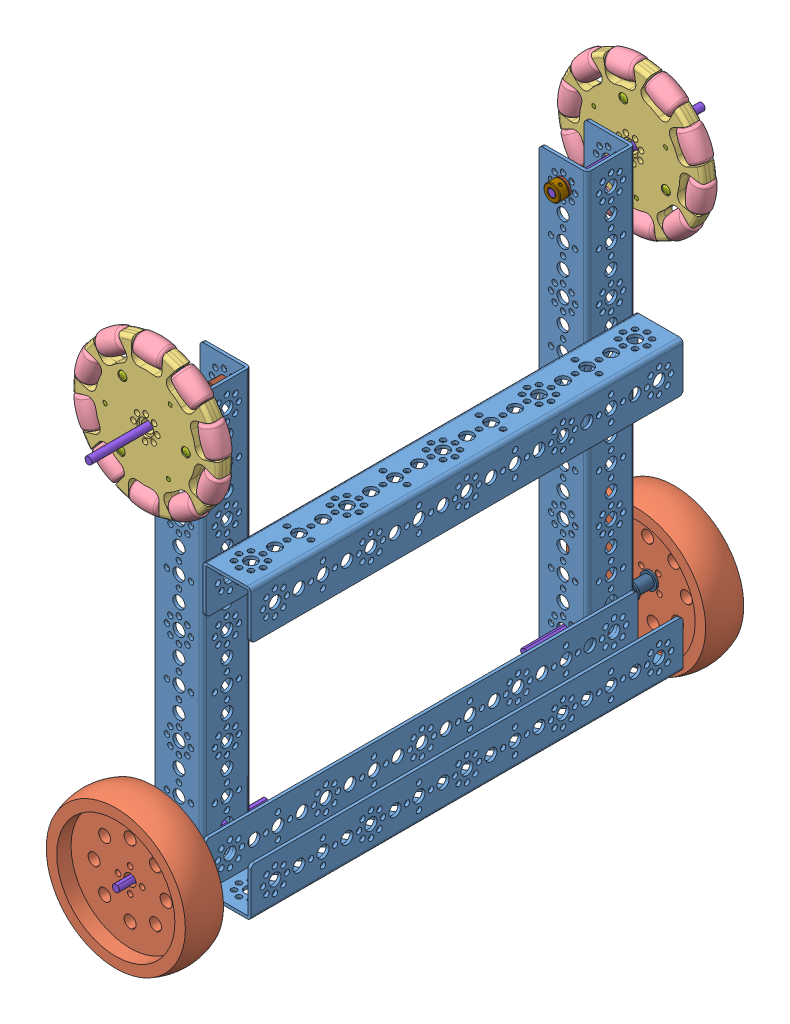
SolidWorks assembly Assem1, configuration Default. Lengths in mm.
Overall size (138.06 393.16 408.8).
138 component instances, 11 part files, 46 mates.
Components (placement in the parent):
- Copy of tetrix_739068^Assem1-1: Copy of tetrix_739068^Assem1 [Default] at origin size (32 32 288) (virtual)
- Copy of tetrix_739068^Assem1-2: Copy of tetrix_739068^Assem1 [Default] at (0 192 0) x (-1 0 0) z (0 0 1) size (32 32 288) (virtual)
- Copy of tetrix_739068^Assem1-3: Copy of tetrix_739068^Assem1 [Default] at (-16 272 -256) x (0 0 -1) z (0 1 0) size (32 32 288) (virtual)
- Copy of tetrix_739068^Assem1-5: Copy of tetrix_739068^Assem1 [Default] at (-16 272 0) x (0 0 -1) z (0 1 0) size (32 32 288) (virtual)
- Copy of tetrix_739055^Assem1-1: Copy of tetrix_739055^Assem1 [Default] at (-32 16 -301.375) x (0.758888 -0.651221 0) z (0 0 1) size (97.6 97.6 25.4) (virtual)
- Copy of tetrix_739055^Assem1-2: Copy of tetrix_739055^Assem1 [Default] at (-32 16 45.375) size (97.6 97.6 25.4) (virtual)
- Copy of tetrix_731132^Assem1-1: Copy of tetrix_731132^Assem1 [Default] at (-32 272 -289.4) x (0.892006 -0.452024 0) z (-0.452024 -0.892006 0) size (103.76 14.46 100.67) (virtual)
  - Copy of tetrix_731132_hub^Copy of tetrix_731132_Assem1-1: Copy of tetrix_731132_hub^Copy of tetrix_731132_Assem1 [Default] at origin size (98 5.15 96.15) (virtual)
  - Copy of tetrix_731132_roller_asm^Copy of tetrix_731132_Assem1-1: Copy of tetrix_731132_roller_asm^Copy of tetrix_731132_Assem1 [Default] at (-0.077 -0.125 43.105) x (1 0 0) z (0 0 -1) size (25.8 14.46 14.46) (virtual)
    - Copy of tetrix_731132_roller^Copy of tetrix_731132_roller_asm_Copy of tetrix_731132_Assem1-1: Copy of tetrix_731132_roller^Copy of tetrix_731132_roller_asm_Copy of tetrix_731132_Assem1 [Default] at origin size (19 14.46 14.46) (virtual)
    - Copy of tetrix_731132_roller_axle^Copy of tetrix_731132_roller_asm_Copy of tetrix_731132_Assem1-1: Copy of tetrix_731132_roller_axle^Copy of tetrix_731132_roller_asm_Copy of tetrix_731132_Assem1 [Default] x (0 0 1) z (-1 0 0) size (3 3 24) (virtual)
    - tetrix_731132_bearing-1: tetrix_731132_bearing [Default] at (-12.9 0 0) x (0 0 -1) z (1 0 0) size (3.25 3.25 3.4)
    - tetrix_731132_bearing-2: tetrix_731132_bearing [Default] at (12.9 0 0) x (0 0 1) z (-1 0 0) size (3.25 3.25 3.4)
  - Copy of tetrix_731132_roller_asm^Copy of tetrix_731132_Assem1-2: Copy of tetrix_731132_roller_asm^Copy of tetrix_731132_Assem1 [Default] at (25.2742 -0.125 34.9179) x (0.809017 0 -0.587785) z (-0.587785 0 -0.809017) size (25.8 14.46 14.46) (virtual)
    - Copy of tetrix_731132_roller^Copy of tetrix_731132_roller_asm_Copy of tetrix_731132_Assem1-1: Copy of tetrix_731132_roller^Copy of tetrix_731132_roller_asm_Copy of tetrix_731132_Assem1 [Default] at origin size (19 14.46 14.46) (virtual)
    - Copy of tetrix_731132_roller_axle^Copy of tetrix_731132_roller_asm_Copy of tetrix_731132_Assem1-1: Copy of tetrix_731132_roller_axle^Copy of tetrix_731132_roller_asm_Copy of tetrix_731132_Assem1 [Default] x (0 0 1) z (-1 0 0) size (3 3 24) (virtual)
    - tetrix_731132_bearing-1: tetrix_731132_bearing [Default] at (-12.9 0 0) x (0 0 -1) z (1 0 0) size (3.25 3.25 3.4)
    - tetrix_731132_bearing-2: tetrix_731132_bearing [Default] at (12.9 0 0) x (0 0 1) z (-1 0 0) size (3.25 3.25 3.4)
  - Copy of tetrix_731132_roller_asm^Copy of tetrix_731132_Assem1-3: Copy of tetrix_731132_roller_asm^Copy of tetrix_731132_Assem1 [Default] at (40.9715 -0.125 13.3934) x (0.309017 0 -0.951057) z (-0.951057 0 -0.309017) size (25.8 14.46 14.46) (virtual)
    - Copy of tetrix_731132_roller^Copy of tetrix_731132_roller_asm_Copy of tetrix_731132_Assem1-1: Copy of tetrix_731132_roller^Copy of tetrix_731132_roller_asm_Copy of tetrix_731132_Assem1 [Default] at origin size (19 14.46 14.46) (virtual)
    - Copy of tetrix_731132_roller_axle^Copy of tetrix_731132_roller_asm_Copy of tetrix_731132_Assem1-1: Copy of tetrix_731132_roller_axle^Copy of tetrix_731132_roller_asm_Copy of tetrix_731132_Assem1 [Default] x (0 0 1) z (-1 0 0) size (3 3 24) (virtual)
    - tetrix_731132_bearing-1: tetrix_731132_bearing [Default] at (-12.9 0 0) x (0 0 -1) z (1 0 0) size (3.25 3.25 3.4)
    - tetrix_731132_bearing-2: tetrix_731132_bearing [Default] at (12.9 0 0) x (0 0 1) z (-1 0 0) size (3.25 3.25 3.4)
  - Copy of tetrix_731132_roller_asm^Copy of tetrix_731132_Assem1-4: Copy of tetrix_731132_roller_asm^Copy of tetrix_731132_Assem1 [Default] at (41.0191 -0.125 -13.2469) x (-0.309017 0 -0.951057) z (-0.951057 0 0.309017) size (25.8 14.46 14.46) (virtual)
    - Copy of tetrix_731132_roller^Copy of tetrix_731132_roller_asm_Copy of tetrix_731132_Assem1-1: Copy of tetrix_731132_roller^Copy of tetrix_731132_roller_asm_Copy of tetrix_731132_Assem1 [Default] at origin size (19 14.46 14.46) (virtual)
    - Copy of tetrix_731132_roller_axle^Copy of tetrix_731132_roller_asm_Copy of tetrix_731132_Assem1-1: Copy of tetrix_731132_roller_axle^Copy of tetrix_731132_roller_asm_Copy of tetrix_731132_Assem1 [Default] x (0 0 1) z (-1 0 0) size (3 3 24) (virtual)
    - tetrix_731132_bearing-1: tetrix_731132_bearing [Default] at (-12.9 0 0) x (0 0 -1) z (1 0 0) size (3.25 3.25 3.4)
    - tetrix_731132_bearing-2: tetrix_731132_bearing [Default] at (12.9 0 0) x (0 0 1) z (-1 0 0) size (3.25 3.25 3.4)
  - Copy of tetrix_731132_roller_asm^Copy of tetrix_731132_Assem1-5: Copy of tetrix_731132_roller_asm^Copy of tetrix_731132_Assem1 [Default] at (25.3988 -0.125 -34.8274) x (-0.809017 0 -0.587785) z (-0.587785 0 0.809017) size (25.8 14.46 14.46) (virtual)
    - Copy of tetrix_731132_roller^Copy of tetrix_731132_roller_asm_Copy of tetrix_731132_Assem1-1: Copy of tetrix_731132_roller^Copy of tetrix_731132_roller_asm_Copy of tetrix_731132_Assem1 [Default] at origin size (19 14.46 14.46) (virtual)
    - Copy of tetrix_731132_roller_axle^Copy of tetrix_731132_roller_asm_Copy of tetrix_731132_Assem1-1: Copy of tetrix_731132_roller_axle^Copy of tetrix_731132_roller_asm_Copy of tetrix_731132_Assem1 [Default] x (0 0 1) z (-1 0 0) size (3 3 24) (virtual)
    - tetrix_731132_bearing-1: tetrix_731132_bearing [Default] at (-12.9 0 0) x (0 0 -1) z (1 0 0) size (3.25 3.25 3.4)
    - tetrix_731132_bearing-2: tetrix_731132_bearing [Default] at (12.9 0 0) x (0 0 1) z (-1 0 0) size (3.25 3.25 3.4)
  - Copy of tetrix_731132_roller_asm^Copy of tetrix_731132_Assem1-6: Copy of tetrix_731132_roller_asm^Copy of tetrix_731132_Assem1 [Default] at (0.077 -0.125 -43.105) x (-1 0 0) z (0 0 1) size (25.8 14.46 14.46) (virtual)
    - Copy of tetrix_731132_roller^Copy of tetrix_731132_roller_asm_Copy of tetrix_731132_Assem1-1: Copy of tetrix_731132_roller^Copy of tetrix_731132_roller_asm_Copy of tetrix_731132_Assem1 [Default] at origin size (19 14.46 14.46) (virtual)
    - Copy of tetrix_731132_roller_axle^Copy of tetrix_731132_roller_asm_Copy of tetrix_731132_Assem1-1: Copy of tetrix_731132_roller_axle^Copy of tetrix_731132_roller_asm_Copy of tetrix_731132_Assem1 [Default] x (0 0 1) z (-1 0 0) size (3 3 24) (virtual)
    - tetrix_731132_bearing-1: tetrix_731132_bearing [Default] at (-12.9 0 0) x (0 0 -1) z (1 0 0) size (3.25 3.25 3.4)
    - tetrix_731132_bearing-2: tetrix_731132_bearing [Default] at (12.9 0 0) x (0 0 1) z (-1 0 0) size (3.25 3.25 3.4)
  - Copy of tetrix_731132_roller_asm^Copy of tetrix_731132_Assem1-7: Copy of tetrix_731132_roller_asm^Copy of tetrix_731132_Assem1 [Default] at (-25.2742 -0.125 -34.9179) x (-0.809017 0 0.587785) z (0.587785 0 0.809017) size (25.8 14.46 14.46) (virtual)
    - Copy of tetrix_731132_roller^Copy of tetrix_731132_roller_asm_Copy of tetrix_731132_Assem1-1: Copy of tetrix_731132_roller^Copy of tetrix_731132_roller_asm_Copy of tetrix_731132_Assem1 [Default] at origin size (19 14.46 14.46) (virtual)
    - Copy of tetrix_731132_roller_axle^Copy of tetrix_731132_roller_asm_Copy of tetrix_731132_Assem1-1: Copy of tetrix_731132_roller_axle^Copy of tetrix_731132_roller_asm_Copy of tetrix_731132_Assem1 [Default] x (0 0 1) z (-1 0 0) size (3 3 24) (virtual)
    - tetrix_731132_bearing-1: tetrix_731132_bearing [Default] at (-12.9 0 0) x (0 0 -1) z (1 0 0) size (3.25 3.25 3.4)
    - tetrix_731132_bearing-2: tetrix_731132_bearing [Default] at (12.9 0 0) x (0 0 1) z (-1 0 0) size (3.25 3.25 3.4)
  - Copy of tetrix_731132_roller_asm^Copy of tetrix_731132_Assem1-8: Copy of tetrix_731132_roller_asm^Copy of tetrix_731132_Assem1 [Default] at (-40.9715 -0.125 -13.3934) x (-0.309017 0 0.951057) z (0.951057 0 0.309017) size (25.8 14.46 14.46) (virtual)
    - Copy of tetrix_731132_roller^Copy of tetrix_731132_roller_asm_Copy of tetrix_731132_Assem1-1: Copy of tetrix_731132_roller^Copy of tetrix_731132_roller_asm_Copy of tetrix_731132_Assem1 [Default] at origin size (19 14.46 14.46) (virtual)
    - Copy of tetrix_731132_roller_axle^Copy of tetrix_731132_roller_asm_Copy of tetrix_731132_Assem1-1: Copy of tetrix_731132_roller_axle^Copy of tetrix_731132_roller_asm_Copy of tetrix_731132_Assem1 [Default] x (0 0 1) z (-1 0 0) size (3 3 24) (virtual)
    - tetrix_731132_bearing-1: tetrix_731132_bearing [Default] at (-12.9 0 0) x (0 0 -1) z (1 0 0) size (3.25 3.25 3.4)
    - tetrix_731132_bearing-2: tetrix_731132_bearing [Default] at (12.9 0 0) x (0 0 1) z (-1 0 0) size (3.25 3.25 3.4)
  - Copy of tetrix_731132_roller_asm^Copy of tetrix_731132_Assem1-9: Copy of tetrix_731132_roller_asm^Copy of tetrix_731132_Assem1 [Default] at (-41.0191 -0.125 13.2469) x (0.309017 0 0.951057) z (0.951057 0 -0.309017) size (25.8 14.46 14.46) (virtual)
    - Copy of tetrix_731132_roller^Copy of tetrix_731132_roller_asm_Copy of tetrix_731132_Assem1-1: Copy of tetrix_731132_roller^Copy of tetrix_731132_roller_asm_Copy of tetrix_731132_Assem1 [Default] at origin size (19 14.46 14.46) (virtual)
    - Copy of tetrix_731132_roller_axle^Copy of tetrix_731132_roller_asm_Copy of tetrix_731132_Assem1-1: Copy of tetrix_731132_roller_axle^Copy of tetrix_731132_roller_asm_Copy of tetrix_731132_Assem1 [Default] x (0 0 1) z (-1 0 0) size (3 3 24) (virtual)
    - tetrix_731132_bearing-1: tetrix_731132_bearing [Default] at (-12.9 0 0) x (0 0 -1) z (1 0 0) size (3.25 3.25 3.4)
    - tetrix_731132_bearing-2: tetrix_731132_bearing [Default] at (12.9 0 0) x (0 0 1) z (-1 0 0) size (3.25 3.25 3.4)
  - Copy of tetrix_731132_roller_asm^Copy of tetrix_731132_Assem1-10: Copy of tetrix_731132_roller_asm^Copy of tetrix_731132_Assem1 [Default] at (-25.3988 -0.125 34.8274) x (0.809017 0 0.587785) z (0.587785 0 -0.809017) size (25.8 14.46 14.46) (virtual)
    - Copy of tetrix_731132_roller^Copy of tetrix_731132_roller_asm_Copy of tetrix_731132_Assem1-1: Copy of tetrix_731132_roller^Copy of tetrix_731132_roller_asm_Copy of tetrix_731132_Assem1 [Default] at origin size (19 14.46 14.46) (virtual)
    - Copy of tetrix_731132_roller_axle^Copy of tetrix_731132_roller_asm_Copy of tetrix_731132_Assem1-1: Copy of tetrix_731132_roller_axle^Copy of tetrix_731132_roller_asm_Copy of tetrix_731132_Assem1 [Default] x (0 0 1) z (-1 0 0) size (3 3 24) (virtual)
    - tetrix_731132_bearing-1: tetrix_731132_bearing [Default] at (-12.9 0 0) x (0 0 -1) z (1 0 0) size (3.25 3.25 3.4)
    - tetrix_731132_bearing-2: tetrix_731132_bearing [Default] at (12.9 0 0) x (0 0 1) z (-1 0 0) size (3.25 3.25 3.4)
  - Copy of tetrix_731132_hub^Copy of tetrix_731132_Assem1-2: Copy of tetrix_731132_hub^Copy of tetrix_731132_Assem1 [Default] x (-1 0 0) z (0 0 1) size (98 5.15 96.15) (virtual)
  - tetrix_731132_screw-1: tetrix_731132_screw [Default] at (-27 -3 0) x (-0.837169 0 -0.546944) z (-0.546944 0 0.837169) size (5.6 10.48 5.64)
  - tetrix_731132_screw-2: tetrix_731132_screw [Default] at (27 3 0) size (5.6 10.48 5.64)
  - tetrix_731132_screw-7: tetrix_731132_screw [Default] at (-15.8702 3 21.8435) size (5.6 10.48 5.64)
  - tetrix_731132_screw-8: tetrix_731132_screw [Default] at (-15.8702 3 -21.8435) size (5.6 10.48 5.64)
  - tetrix_731132_screw-9: tetrix_731132_screw [Default] at (15.8702 -3 21.8435) x (-0.837169 0 -0.546944) z (-0.546944 0 0.837169) size (5.6 10.48 5.64)
  - tetrix_731132_screw-10: tetrix_731132_screw [Default] at (15.8702 -3 -21.8435) x (-0.837169 0 -0.546944) z (-0.546944 0 0.837169) size (5.6 10.48 5.64)
- Copy of tetrix_731132^Assem1-2: Copy of tetrix_731132^Assem1 [Default] at (-32 272 33.4) x (0.999671 -0.025666 0) z (-0.025666 -0.999671 0) size (103.76 14.46 100.67) (virtual)
  - Copy of tetrix_731132_hub^Copy of tetrix_731132_Assem1-1: Copy of tetrix_731132_hub^Copy of tetrix_731132_Assem1 [Default] at origin size (98 5.15 96.15) (virtual)
  - Copy of tetrix_731132_roller_asm^Copy of tetrix_731132_Assem1-1: Copy of tetrix_731132_roller_asm^Copy of tetrix_731132_Assem1 [Default] at (-0.077 -0.125 43.105) x (1 0 0) z (0 0 -1) size (25.8 14.46 14.46) (virtual)
    - Copy of tetrix_731132_roller^Copy of tetrix_731132_roller_asm_Copy of tetrix_731132_Assem1-1: Copy of tetrix_731132_roller^Copy of tetrix_731132_roller_asm_Copy of tetrix_731132_Assem1 [Default] at origin size (19 14.46 14.46) (virtual)
    - Copy of tetrix_731132_roller_axle^Copy of tetrix_731132_roller_asm_Copy of tetrix_731132_Assem1-1: Copy of tetrix_731132_roller_axle^Copy of tetrix_731132_roller_asm_Copy of tetrix_731132_Assem1 [Default] x (0 0 1) z (-1 0 0) size (3 3 24) (virtual)
    - tetrix_731132_bearing-1: tetrix_731132_bearing [Default] at (-12.9 0 0) x (0 0 -1) z (1 0 0) size (3.25 3.25 3.4)
    - tetrix_731132_bearing-2: tetrix_731132_bearing [Default] at (12.9 0 0) x (0 0 1) z (-1 0 0) size (3.25 3.25 3.4)
  - Copy of tetrix_731132_roller_asm^Copy of tetrix_731132_Assem1-2: Copy of tetrix_731132_roller_asm^Copy of tetrix_731132_Assem1 [Default] at (25.2742 -0.125 34.9179) x (0.809017 0 -0.587785) z (-0.587785 0 -0.809017) size (25.8 14.46 14.46) (virtual)
    - Copy of tetrix_731132_roller^Copy of tetrix_731132_roller_asm_Copy of tetrix_731132_Assem1-1: Copy of tetrix_731132_roller^Copy of tetrix_731132_roller_asm_Copy of tetrix_731132_Assem1 [Default] at origin size (19 14.46 14.46) (virtual)
    - Copy of tetrix_731132_roller_axle^Copy of tetrix_731132_roller_asm_Copy of tetrix_731132_Assem1-1: Copy of tetrix_731132_roller_axle^Copy of tetrix_731132_roller_asm_Copy of tetrix_731132_Assem1 [Default] x (0 0 1) z (-1 0 0) size (3 3 24) (virtual)
    - tetrix_731132_bearing-1: tetrix_731132_bearing [Default] at (-12.9 0 0) x (0 0 -1) z (1 0 0) size (3.25 3.25 3.4)
    - tetrix_731132_bearing-2: tetrix_731132_bearing [Default] at (12.9 0 0) x (0 0 1) z (-1 0 0) size (3.25 3.25 3.4)
  - Copy of tetrix_731132_roller_asm^Copy of tetrix_731132_Assem1-3: Copy of tetrix_731132_roller_asm^Copy of tetrix_731132_Assem1 [Default] at (40.9715 -0.125 13.3934) x (0.309017 0 -0.951057) z (-0.951057 0 -0.309017) size (25.8 14.46 14.46) (virtual)
    - Copy of tetrix_731132_roller^Copy of tetrix_731132_roller_asm_Copy of tetrix_731132_Assem1-1: Copy of tetrix_731132_roller^Copy of tetrix_731132_roller_asm_Copy of tetrix_731132_Assem1 [Default] at origin size (19 14.46 14.46) (virtual)
    - Copy of tetrix_731132_roller_axle^Copy of tetrix_731132_roller_asm_Copy of tetrix_731132_Assem1-1: Copy of tetrix_731132_roller_axle^Copy of tetrix_731132_roller_asm_Copy of tetrix_731132_Assem1 [Default] x (0 0 1) z (-1 0 0) size (3 3 24) (virtual)
    - tetrix_731132_bearing-1: tetrix_731132_bearing [Default] at (-12.9 0 0) x (0 0 -1) z (1 0 0) size (3.25 3.25 3.4)
    - tetrix_731132_bearing-2: tetrix_731132_bearing [Default] at (12.9 0 0) x (0 0 1) z (-1 0 0) size (3.25 3.25 3.4)
  - Copy of tetrix_731132_roller_asm^Copy of tetrix_731132_Assem1-4: Copy of tetrix_731132_roller_asm^Copy of tetrix_731132_Assem1 [Default] at (41.0191 -0.125 -13.2469) x (-0.309017 0 -0.951057) z (-0.951057 0 0.309017) size (25.8 14.46 14.46) (virtual)
    - Copy of tetrix_731132_roller^Copy of tetrix_731132_roller_asm_Copy of tetrix_731132_Assem1-1: Copy of tetrix_731132_roller^Copy of tetrix_731132_roller_asm_Copy of tetrix_731132_Assem1 [Default] at origin size (19 14.46 14.46) (virtual)
    - Copy of tetrix_731132_roller_axle^Copy of tetrix_731132_roller_asm_Copy of tetrix_731132_Assem1-1: Copy of tetrix_731132_roller_axle^Copy of tetrix_731132_roller_asm_Copy of tetrix_731132_Assem1 [Default] x (0 0 1) z (-1 0 0) size (3 3 24) (virtual)
    - tetrix_731132_bearing-1: tetrix_731132_bearing [Default] at (-12.9 0 0) x (0 0 -1) z (1 0 0) size (3.25 3.25 3.4)
    - tetrix_731132_bearing-2: tetrix_731132_bearing [Default] at (12.9 0 0) x (0 0 1) z (-1 0 0) size (3.25 3.25 3.4)
  - Copy of tetrix_731132_roller_asm^Copy of tetrix_731132_Assem1-5: Copy of tetrix_731132_roller_asm^Copy of tetrix_731132_Assem1 [Default] at (25.3988 -0.125 -34.8274) x (-0.809017 0 -0.587785) z (-0.587785 0 0.809017) size (25.8 14.46 14.46) (virtual)
    - Copy of tetrix_731132_roller^Copy of tetrix_731132_roller_asm_Copy of tetrix_731132_Assem1-1: Copy of tetrix_731132_roller^Copy of tetrix_731132_roller_asm_Copy of tetrix_731132_Assem1 [Default] at origin size (19 14.46 14.46) (virtual)
    - Copy of tetrix_731132_roller_axle^Copy of tetrix_731132_roller_asm_Copy of tetrix_731132_Assem1-1: Copy of tetrix_731132_roller_axle^Copy of tetrix_731132_roller_asm_Copy of tetrix_731132_Assem1 [Default] x (0 0 1) z (-1 0 0) size (3 3 24) (virtual)
    - tetrix_731132_bearing-1: tetrix_731132_bearing [Default] at (-12.9 0 0) x (0 0 -1) z (1 0 0) size (3.25 3.25 3.4)
    - tetrix_731132_bearing-2: tetrix_731132_bearing [Default] at (12.9 0 0) x (0 0 1) z (-1 0 0) size (3.25 3.25 3.4)
  - Copy of tetrix_731132_roller_asm^Copy of tetrix_731132_Assem1-6: Copy of tetrix_731132_roller_asm^Copy of tetrix_731132_Assem1 [Default] at (0.077 -0.125 -43.105) x (-1 0 0) z (0 0 1) size (25.8 14.46 14.46) (virtual)
    - Copy of tetrix_731132_roller^Copy of tetrix_731132_roller_asm_Copy of tetrix_731132_Assem1-1: Copy of tetrix_731132_roller^Copy of tetrix_731132_roller_asm_Copy of tetrix_731132_Assem1 [Default] at origin size (19 14.46 14.46) (virtual)
    - Copy of tetrix_731132_roller_axle^Copy of tetrix_731132_roller_asm_Copy of tetrix_731132_Assem1-1: Copy of tetrix_731132_roller_axle^Copy of tetrix_731132_roller_asm_Copy of tetrix_731132_Assem1 [Default] x (0 0 1) z (-1 0 0) size (3 3 24) (virtual)
    - tetrix_731132_bearing-1: tetrix_731132_bearing [Default] at (-12.9 0 0) x (0 0 -1) z (1 0 0) size (3.25 3.25 3.4)
    - tetrix_731132_bearing-2: tetrix_731132_bearing [Default] at (12.9 0 0) x (0 0 1) z (-1 0 0) size (3.25 3.25 3.4)
  - Copy of tetrix_731132_roller_asm^Copy of tetrix_731132_Assem1-7: Copy of tetrix_731132_roller_asm^Copy of tetrix_731132_Assem1 [Default] at (-25.2742 -0.125 -34.9179) x (-0.809017 0 0.587785) z (0.587785 0 0.809017) size (25.8 14.46 14.46) (virtual)
    - Copy of tetrix_731132_roller^Copy of tetrix_731132_roller_asm_Copy of tetrix_731132_Assem1-1: Copy of tetrix_731132_roller^Copy of tetrix_731132_roller_asm_Copy of tetrix_731132_Assem1 [Default] at origin size (19 14.46 14.46) (virtual)
    - Copy of tetrix_731132_roller_axle^Copy of tetrix_731132_roller_asm_Copy of tetrix_731132_Assem1-1: Copy of tetrix_731132_roller_axle^Copy of tetrix_731132_roller_asm_Copy of tetrix_731132_Assem1 [Default] x (0 0 1) z (-1 0 0) size (3 3 24) (virtual)
    - tetrix_731132_bearing-1: tetrix_731132_bearing [Default] at (-12.9 0 0) x (0 0 -1) z (1 0 0) size (3.25 3.25 3.4)
    - tetrix_731132_bearing-2: tetrix_731132_bearing [Default] at (12.9 0 0) x (0 0 1) z (-1 0 0) size (3.25 3.25 3.4)
  - Copy of tetrix_731132_roller_asm^Copy of tetrix_731132_Assem1-8: Copy of tetrix_731132_roller_asm^Copy of tetrix_731132_Assem1 [Default] at (-40.9715 -0.125 -13.3934) x (-0.309017 0 0.951057) z (0.951057 0 0.309017) size (25.8 14.46 14.46) (virtual)
    - Copy of tetrix_731132_roller^Copy of tetrix_731132_roller_asm_Copy of tetrix_731132_Assem1-1: Copy of tetrix_731132_roller^Copy of tetrix_731132_roller_asm_Copy of tetrix_731132_Assem1 [Default] at origin size (19 14.46 14.46) (virtual)
    - Copy of tetrix_731132_roller_axle^Copy of tetrix_731132_roller_asm_Copy of tetrix_731132_Assem1-1: Copy of tetrix_731132_roller_axle^Copy of tetrix_731132_roller_asm_Copy of tetrix_731132_Assem1 [Default] x (0 0 1) z (-1 0 0) size (3 3 24) (virtual)
    - tetrix_731132_bearing-1: tetrix_731132_bearing [Default] at (-12.9 0 0) x (0 0 -1) z (1 0 0) size (3.25 3.25 3.4)
    - tetrix_731132_bearing-2: tetrix_731132_bearing [Default] at (12.9 0 0) x (0 0 1) z (-1 0 0) size (3.25 3.25 3.4)
  - Copy of tetrix_731132_roller_asm^Copy of tetrix_731132_Assem1-9: Copy of tetrix_731132_roller_asm^Copy of tetrix_731132_Assem1 [Default] at (-41.0191 -0.125 13.2469) x (0.309017 0 0.951057) z (0.951057 0 -0.309017) size (25.8 14.46 14.46) (virtual)
    - Copy of tetrix_731132_roller^Copy of tetrix_731132_roller_asm_Copy of tetrix_731132_Assem1-1: Copy of tetrix_731132_roller^Copy of tetrix_731132_roller_asm_Copy of tetrix_731132_Assem1 [Default] at origin size (19 14.46 14.46) (virtual)
    - Copy of tetrix_731132_roller_axle^Copy of tetrix_731132_roller_asm_Copy of tetrix_731132_Assem1-1: Copy of tetrix_731132_roller_axle^Copy of tetrix_731132_roller_asm_Copy of tetrix_731132_Assem1 [Default] x (0 0 1) z (-1 0 0) size (3 3 24) (virtual)
    - tetrix_731132_bearing-1: tetrix_731132_bearing [Default] at (-12.9 0 0) x (0 0 -1) z (1 0 0) size (3.25 3.25 3.4)
    - tetrix_731132_bearing-2: tetrix_731132_bearing [Default] at (12.9 0 0) x (0 0 1) z (-1 0 0) size (3.25 3.25 3.4)
  - Copy of tetrix_731132_roller_asm^Copy of tetrix_731132_Assem1-10: Copy of tetrix_731132_roller_asm^Copy of tetrix_731132_Assem1 [Default] at (-25.3988 -0.125 34.8274) x (0.809017 0 0.587785) z (0.587785 0 -0.809017) size (25.8 14.46 14.46) (virtual)
    - Copy of tetrix_731132_roller^Copy of tetrix_731132_roller_asm_Copy of tetrix_731132_Assem1-1: Copy of tetrix_731132_roller^Copy of tetrix_731132_roller_asm_Copy of tetrix_731132_Assem1 [Default] at origin size (19 14.46 14.46) (virtual)
    - Copy of tetrix_731132_roller_axle^Copy of tetrix_731132_roller_asm_Copy of tetrix_731132_Assem1-1: Copy of tetrix_731132_roller_axle^Copy of tetrix_731132_roller_asm_Copy of tetrix_731132_Assem1 [Default] x (0 0 1) z (-1 0 0) size (3 3 24) (virtual)
    - tetrix_731132_bearing-1: tetrix_731132_bearing [Default] at (-12.9 0 0) x (0 0 -1) z (1 0 0) size (3.25 3.25 3.4)
    - tetrix_731132_bearing-2: tetrix_731132_bearing [Default] at (12.9 0 0) x (0 0 1) z (-1 0 0) size (3.25 3.25 3.4)
  - Copy of tetrix_731132_hub^Copy of tetrix_731132_Assem1-2: Copy of tetrix_731132_hub^Copy of tetrix_731132_Assem1 [Default] x (-1 0 0) z (0 0 1) size (98 5.15 96.15) (virtual)
  - tetrix_731132_screw-1: tetrix_731132_screw [Default] at (-27 -3 0) x (-0.837169 0 -0.546944) z (-0.546944 0 0.837169) size (5.6 10.48 5.64)
  - tetrix_731132_screw-2: tetrix_731132_screw [Default] at (27 3 0) size (5.6 10.48 5.64)
  - tetrix_731132_screw-7: tetrix_731132_screw [Default] at (-15.8702 3 21.8435) size (5.6 10.48 5.64)
  - tetrix_731132_screw-8: tetrix_731132_screw [Default] at (-15.8702 3 -21.8435) size (5.6 10.48 5.64)
  - tetrix_731132_screw-9: tetrix_731132_screw [Default] at (15.8702 -3 21.8435) x (-0.837169 0 -0.546944) z (-0.546944 0 0.837169) size (5.6 10.48 5.64)
  - tetrix_731132_screw-10: tetrix_731132_screw [Default] at (15.8702 -3 -21.8435) x (-0.837169 0 -0.546944) z (-0.546944 0 0.837169) size (5.6 10.48 5.64)
- Copy of tetrix_739088^Assem1-1: Copy of tetrix_739088^Assem1 [Default] at (-32 16 -264.075) x (0.942817 0.333311 0) z (0 0 1) size (4.73 4.46 100) (virtual)
- Copy of tetrix_739088^Assem1-2: Copy of tetrix_739088^Assem1 [Default] at (-32 16 8.075) size (4.73 4.46 100) (virtual)
- Copy of tetrix_739092_collar^Assem1-1: Copy of tetrix_739092_collar^Assem1 [Default] at (-32 272 -20.5) size (11 11 6.2) (virtual)
- Copy of tetrix_739092_collar^Assem1-2: Copy of tetrix_739092_collar^Assem1 [Default] at (-32 272 -235.5) x (0.501001 0.865447 0) z (0 0 1) size (11 11 6.2) (virtual)
- Copy of tetrix_739091^Assem1-1: Copy of tetrix_739091^Assem1 [Default] at (-32 16 29.8) x (0.907965 -0.419046 0) z (0.419046 0.907965 0) size (11 12.4 11) (virtual)
- Copy of tetrix_739091^Assem1-2: Copy of tetrix_739091^Assem1 [Default] at (-32 16 -273.4) x (1 0 0) z (0 -1 0) size (11 12.4 11) (virtual)
- Copy of tetrix_739091^Assem1-3: Copy of tetrix_739091^Assem1 [Default] at (-32 16 17.4) x (0.78991 0.613223 0) z (-0.613223 0.78991 0) size (11 12.4 11) (virtual)
- Copy of tetrix_739091^Assem1-4: Copy of tetrix_739091^Assem1 [Default] at (-32 16 -298.2) x (-0.180235 0.983624 0) z (0.983624 0.180235 0) size (11 12.4 11) (virtual)
- Copy of tetrix_739091^Assem1-5: Copy of tetrix_739091^Assem1 [Default] at (-32 16 42.2) x (1 0 0) z (0 1 0) size (11 12.4 11) (virtual)
- Copy of tetrix_739091^Assem1-6: Copy of tetrix_739091^Assem1 [Default] at (-32 16 -285.8) x (0.731305 -0.682051 0) z (-0.682051 -0.731305 0) size (11 12.4 11) (virtual)
- Copy of tetrix_739088^Assem1-3: Copy of tetrix_739088^Assem1 [Default] at (-32 272 26.4) x (-0.215051 0.976603 0) z (0 0 1) size (4.73 4.46 100) (virtual)
- Copy of tetrix_739088^Assem1-4: Copy of tetrix_739088^Assem1 [Default] at (-32 272 -282.4) x (-0.5071 0.861888 0) z (0 0 1) size (4.73 4.46 100) (virtual)
- Copy (2) of tetrix_739091^Assem1-7: Copy (2) of tetrix_739091^Assem1 [Default] at (-32 272 -17.4) x (0.574061 -0.818813 0) z (-0.818813 -0.574061 0) size (11 12.4 11) (virtual)
- Copy (2) of tetrix_739091^Assem1-8: Copy (2) of tetrix_739091^Assem1 [Default] at (-32 272 -238.6) x (0.051692 0.998663 0) z (-0.998663 0.051692 0) size (11 12.4 11) (virtual)
Mates (geometry in assembly coordinates):
- Coincident1: coordinate: point of Copy of tetrix_739068^Assem1-1
- Concentric2: concentric anti-aligned: cylinder of Copy of tetrix_739068^Assem1-1 through (-16 16 0) axis (-1 0 0) radius 4; cylinder of Copy of tetrix_739068^Assem1-5 through (-16 16 0) axis (1 0 0) radius 4
- Coincident4: coincident anti-aligned: plane of Copy of tetrix_739068^Assem1-1 through (-16 0 0) normal (-1 0 0); plane of Copy of tetrix_739068^Assem1-5 through (-16 288 16) normal (1 0 0)
- Coincident5: coincident aligned: plane of Copy of tetrix_739068^Assem1-1 through (-16 32 16) normal (0 0 1); plane of Copy of tetrix_739068^Assem1-5 through (-16 272 16) normal (0 0 1)
- Concentric3: concentric anti-aligned: cylinder of Copy of tetrix_739068^Assem1-1 through (-16 16 -256) axis (-1 0 0) radius 4; cylinder of Copy of tetrix_739068^Assem1-3 through (-16 16 -256) axis (1 0 0) radius 4
- Coincident6: coincident anti-aligned: plane of Copy of tetrix_739068^Assem1-1 through (-16 0 0) normal (-1 0 0); plane of Copy of tetrix_739068^Assem1-3 through (-16 288 -240) normal (1 0 0)
- Coincident7: coincident aligned: plane of Copy of tetrix_739068^Assem1-1 through (-16 0 -272) normal (0 0 -1); plane of Copy of tetrix_739068^Assem1-3 through (-16 272 -272) normal (0 0 -1)
- Concentric4: concentric anti-aligned: cylinder of Copy of tetrix_739068^Assem1-2 through (-16 176 0) axis (-1 0 0) radius 4; cylinder of Copy of tetrix_739068^Assem1-5 through (-16 176 0) axis (1 0 0) radius 4
- Concentric5: concentric anti-aligned: cylinder of Copy of tetrix_739068^Assem1-2 through (-16 176 -256) axis (-1 0 0) radius 4; cylinder of Copy of tetrix_739068^Assem1-3 through (-16 176 -256) axis (1 0 0) radius 4
- Coincident8: coincident anti-aligned: plane of Copy of tetrix_739068^Assem1-2 through (-16 192 0) normal (-1 0 0); plane of Copy of tetrix_739068^Assem1-3 through (-16 288 -240) normal (1 0 0)
- Concentric6: concentric anti-aligned: cylinder of Copy of tetrix_739068^Assem1-5 through (-32 16 -16) axis (0 0 -1) radius 4; cylinder of Copy of tetrix_739088^Assem1-2 through (-32 16 -41.925) axis (0 0 1) radius 2.365
- Concentric7: concentric anti-aligned: cylinder of Copy of tetrix_739068^Assem1-3 through (-32 16 -272) axis (0 0 -1) radius 4; cylinder of Copy of tetrix_739088^Assem1-1 through (-32 16 -314.075) axis (0 0 1) radius 2.365
- Concentric8: concentric anti-aligned: circle of Copy of tetrix_739068^Assem1-5; cylinder of Copy of tetrix_739088^Assem1-3 through (-32 272 -23.6) axis (0 0 1) radius 2.365
- Concentric9: concentric anti-aligned: cylinder of Copy of tetrix_739068^Assem1-3 through (-32 272 -272) axis (0 0 -1) radius 4; cylinder of Copy of tetrix_739088^Assem1-4 through (-32 272 -332.4) axis (0 0 1) radius 2.365
- Concentric10: concentric aligned: cylinder of Copy of tetrix_739055^Assem1-2 through (-32 16 32.675) axis (0 0 1) radius 4; cylinder of Copy of tetrix_739088^Assem1-2 through (-32 16 -41.925) axis (0 0 1) radius 2.365
- Concentric11: concentric aligned: cylinder of Copy of tetrix_739055^Assem1-1 through (-32 16 -314.075) axis (0 0 1) radius 4; cylinder of Copy of tetrix_739088^Assem1-1 through (-32 16 -314.075) axis (0 0 1) radius 2.365
- Concentric12: concentric anti-aligned: cylinder of Copy of tetrix_731132^Assem1-2/Copy of tetrix_731132_hub^Copy of tetrix_731132_Assem1-2 through (-32 272 28.4) axis (0 0 -1) radius 4.05; cylinder of Copy of tetrix_739088^Assem1-3 through (-32 272 -23.6) axis (0 0 1) radius 2.365
- Concentric13: concentric anti-aligned: cylinder of Copy of tetrix_731132^Assem1-1/Copy of tetrix_731132_hub^Copy of tetrix_731132_Assem1-2 through (-32 272 -294.4) axis (0 0 -1) radius 4.05; cylinder of Copy of tetrix_739088^Assem1-4 through (-32 272 -332.4) axis (0 0 1) radius 2.365
- Concentric14: concentric aligned: cylinder of Copy of tetrix_739092_collar^Assem1-1 through (-32 272 -17.4) axis (0 0 1) radius 2.425; cylinder of Copy of tetrix_739088^Assem1-3 through (-32 272 -23.6) axis (0 0 1) radius 2.365
- Coincident9: coincident aligned: plane of Copy of tetrix_739092_collar^Assem1-1 through (-26.5 272 -23.6) normal (0 0 -1); plane of Copy of tetrix_739088^Assem1-3 through (-32 272 -23.6) normal (0 0 -1)
- Concentric15: concentric aligned: cylinder of Copy of tetrix_739092_collar^Assem1-2 through (-32 272 -232.4) axis (0 0 1) radius 2.425; cylinder of Copy of tetrix_739088^Assem1-4 through (-32 272 -332.4) axis (0 0 1) radius 2.365
- Coincident10: coincident aligned: plane of Copy of tetrix_739092_collar^Assem1-2 through (-32 272 -232.4) normal (0 0 1); plane of Copy of tetrix_739088^Assem1-4 through (-32 272 -232.4) normal (0 0 1)
- Coincident11: coincident anti-aligned: plane of Copy of tetrix_739055^Assem1-2 through (-28 16 42.2) normal (0 0 -1); plane of Copy of tetrix_739091^Assem1-5 through (-26.5 16 42.2) normal (0 0 1)
- Concentric16: concentric anti-aligned: cylinder of Copy of tetrix_739088^Assem1-2 through (-32 16 -41.925) axis (0 0 1) radius 2.365; cylinder of Copy of tetrix_739091^Assem1-5 through (-32 16 42.2) axis (0 0 -1) radius 2.4
- Concentric17: concentric anti-aligned: cylinder of Copy of tetrix_739088^Assem1-2 through (-32 16 -41.925) axis (0 0 1) radius 2.365; cylinder of Copy of tetrix_739091^Assem1-1 through (-32 16 29.8) axis (0 0 -1) radius 2.4
- Concentric18: concentric anti-aligned: cylinder of Copy of tetrix_739088^Assem1-2 through (-32 16 -41.925) axis (0 0 1) radius 2.365; cylinder of Copy of tetrix_739091^Assem1-3 through (-32 16 17.4) axis (0 0 -1) radius 2.4
- Concentric19: concentric aligned: cylinder of Copy of tetrix_739088^Assem1-1 through (-32 16 -314.075) axis (0 0 1) radius 2.365; cylinder of Copy of tetrix_739091^Assem1-4 through (-32 16 -298.2) axis (0 0 1) radius 2.4
- Concentric20: concentric aligned: cylinder of Copy of tetrix_739088^Assem1-1 through (-32 16 -314.075) axis (0 0 1) radius 2.365; cylinder of Copy of tetrix_739091^Assem1-6 through (-32 16 -285.8) axis (0 0 1) radius 2.4
- Concentric21: concentric aligned: cylinder of Copy of tetrix_739088^Assem1-1 through (-32 16 -314.075) axis (0 0 1) radius 2.365; cylinder of Copy of tetrix_739091^Assem1-2 through (-32 16 -273.4) axis (0 0 1) radius 2.4
- Coincident12: coincident anti-aligned: plane of Copy of tetrix_739091^Assem1-4 through (-32.4326 18.3607 -285.8) normal (0 0 1); plane of Copy of tetrix_739091^Assem1-6 through (-27.9778 12.2487 -285.8) normal (0 0 -1)
- Coincident13: coincident anti-aligned: plane of Copy of tetrix_739091^Assem1-2 through (-26.5 16 -273.4) normal (0 0 -1); plane of Copy of tetrix_739091^Assem1-6 through (-30.2449 14.3631 -273.4) normal (0 0 1)
- Coincident14: coincident anti-aligned: plane of Copy of tetrix_739055^Assem1-1 through (-2.1226 -9.6386 -298.2) normal (0 0 1); plane of Copy of tetrix_739091^Assem1-4 through (-32.9913 21.4099 -298.2) normal (0 0 -1)
- Coincident15: coincident anti-aligned: plane of Copy of tetrix_739068^Assem1-3 through (-16 272 -272) normal (0 0 -1); plane of Copy of tetrix_739091^Assem1-2 through (-28.075 16 -272) normal (0 0 1)
- Coincident16: coincident aligned: plane of Copy of tetrix_739055^Assem1-1 through (3.1661 -14.177 -314.075) normal (0 0 -1); plane of Copy of tetrix_739088^Assem1-1 through (-32 16 -314.075) normal (0 0 -1)
- Coincident17: coincident anti-aligned: plane of Copy of tetrix_739091^Assem1-1 through (-27.0062 13.6952 29.8) normal (0 0 1); plane of Copy of tetrix_739091^Assem1-5 through (-29.6 16 29.8) normal (0 0 -1)
- Coincident18: coincident anti-aligned: plane of Copy of tetrix_739091^Assem1-1 through (-29.8209 14.9943 17.4) normal (0 0 -1); plane of Copy of tetrix_739091^Assem1-3 through (-27.6555 19.3727 17.4) normal (0 0 1)
- Coincident19: coincident anti-aligned: plane of Copy of tetrix_739068^Assem1-5 through (-16 272 16) normal (0 0 1); plane of Copy of tetrix_739091^Assem1-3 through (-28.8996 18.4069 16) normal (0 0 -1)
- Coincident20: coincident aligned: plane of Copy of tetrix_739055^Assem1-2 through (-32 16 58.075) normal (0 0 1); plane of Copy of tetrix_739088^Assem1-2 through (-32 16 58.075) normal (0 0 1)
- Concentric22: concentric anti-aligned: cylinder of Copy of tetrix_739088^Assem1-4 through (-32 272 -332.4) axis (0 0 1) radius 2.365; cylinder of Copy (2) of tetrix_739091^Assem1-8 through (-32 272 -238.6) axis (0 0 -1) radius 2.4
- Concentric23: concentric aligned: cylinder of Copy of tetrix_739088^Assem1-3 through (-32 272 -23.6) axis (0 0 1) radius 2.365; cylinder of Copy (2) of tetrix_739091^Assem1-7 through (-32 272 -17.4) axis (0 0 1) radius 2.4
- Coincident21: coincident anti-aligned: plane of Copy of tetrix_739092_collar^Assem1-1 through (-32 272 -17.4) normal (0 0 1); plane of Copy (2) of tetrix_739091^Assem1-7 through (-28.8427 267.4965 -17.4) normal (0 0 -1)
- Coincident22: coincident anti-aligned: plane of Copy of tetrix_739092_collar^Assem1-2 through (-29.2445 276.76 -238.6) normal (0 0 -1); plane of Copy (2) of tetrix_739091^Assem1-8 through (-31.7157 277.4926 -238.6) normal (0 0 1)
- Coincident23: coincident anti-aligned: plane of Copy of tetrix_739068^Assem1-3 through (-16 272 -240) normal (0 0 1); plane of Copy (2) of tetrix_739091^Assem1-8 through (-31.7971 275.9198 -240) normal (0 0 -1)
- Coincident24: coincident anti-aligned: plane of Copy of tetrix_739068^Assem1-5 through (-16 272 -16) normal (0 0 -1); plane of Copy (2) of tetrix_739091^Assem1-7 through (-29.7468 268.7862 -16) normal (0 0 1)
- Coincident25: coincident aligned: plane of Copy of tetrix_731132^Assem1-2/Copy of tetrix_731132_hub^Copy of tetrix_731132_Assem1-2 through (-32 272 28.4) normal (0 0 -1); plane of Copy of tetrix_739091^Assem1-1 through (-28.4362 14.3552 28.4) normal (0 0 -1)
- Coincident26: coincident aligned: plane of Copy of tetrix_731132^Assem1-1/Copy of tetrix_731132_hub^Copy of tetrix_731132_Assem1-1 through (-32 272 -284.4) normal (0 0 1); plane of Copy of tetrix_739091^Assem1-6 through (-29.1296 13.3229 -284.4) normal (0 0 1)
